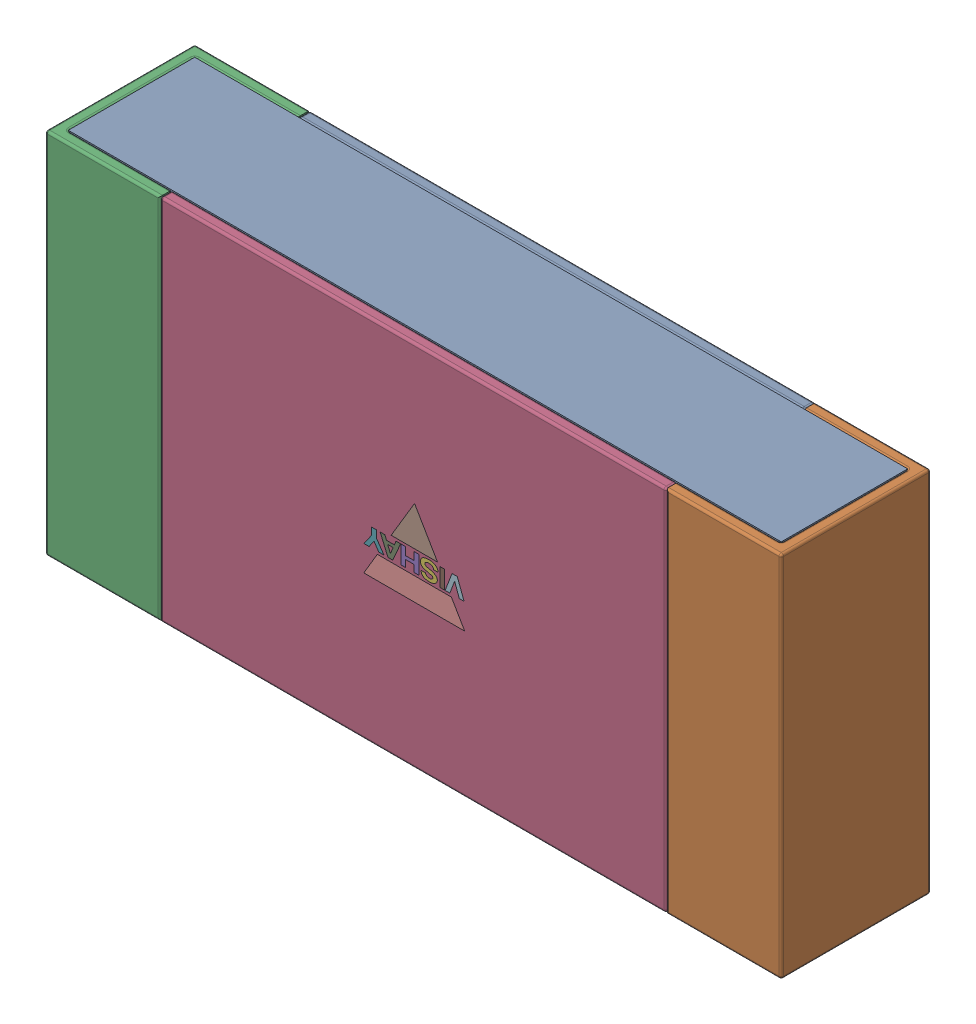
SolidWorks assembly res1, configuration Défaut. Lengths in mm.
Overall size (3.2 1.6 0.65).
7 component instances, 5 part files, 0 mates.
Components (placement in the parent):
- Res_Vishay_MCA12060D1541BP100_eec-1: Res_Vishay_MCA12060D1541BP100_eec [Défaut] at (-14.097 33.274 0) x (-1 0 0) z (0 0 1) size (3.2 1.6 0.65)
  - body-1: body [Défaut] at (0 0 0.6) x (1 0 0) z (0 0 -1) size (3.1 1.6 0.55)
  - pad-1: pad [Défaut] at (-1.4133 -0.8 0.65) x (1 0 0) z (0 1 0) size (0.5 0.65 1.6)
  - pad-2: pad [Défaut] at (1.4133 0.8 0.65) x (-1 0 0) z (0 -1 0) size (0.5 0.65 1.6)
  - top-1: top [Défaut] at (0 0 0.65) x (1 0 0) z (0 0 -1) size (2.2 1.6 0.05)
  - Vishay-1: Vishay [Défaut] at (0.0405 -0.7888 0.65) size (0.45 0.38 0.01)
  - bottom-1: bottom [Défaut] at (0 0 0.05) x (1 0 0) z (0 0 -1) size (2.2 1.6 0.05)
